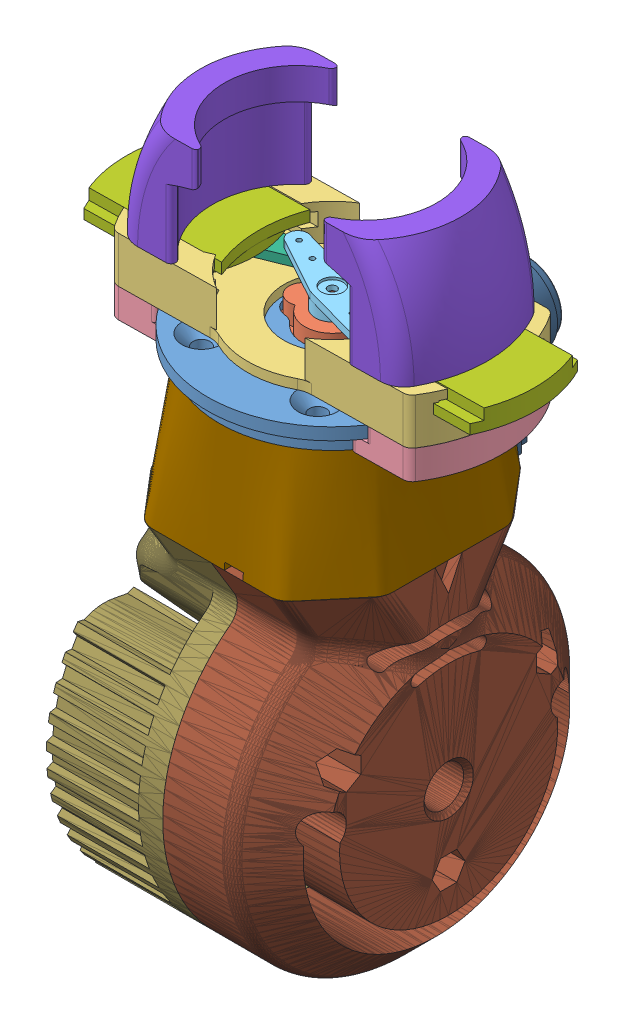
SolidWorks assembly Схват2, configuration По умолчанию. Lengths in mm.
Overall size (84.15 139 75.5).
16 component instances, 12 part files, 77 mates.
Components (placement in the parent):
- Рельс_v3-1: Рельс_v3 [По умолчанию] at (-57.4997 -6.93 31.9738) size (51.5 6 51.5)
- servo_micro-1: servo_micro [По умолчанию] at (-45.8497 -25.18 12.7238) x (1 0 0) z (0 -1 0) size (33 12.5 29.75)
- Рельс_3-1: Рельс_3 [По умолчанию] at (1.2832 -0.68 3.5473) x (-0.999898 0 0.01427) z (-0.01427 0 -0.999898) size (69.76 9.5 35)
- Накладка-1: Накладка [По умолчанию] at (-28.4997 -6.68 18.9738) x (-0.999898 0 0.01427) z (-0.01427 0 -0.999898) size (16.69 6 30)
- Накладка-2: Накладка [По умолчанию] at (-28.4997 -6.68 18.9738) x (0.999898 0 -0.01427) z (0.01427 0 0.999898) size (16.69 6 30)
- servo_lever-1: servo_lever [По умолчанию] at (-28.4997 6.07 18.9738) x (-0.377303 0 0.92609) z (0.92609 0 0.377303) size (7 4 30)
- Балка_2_EDIT-1: Балка_2_EDIT [По умолчанию] at (-0.0451 4.57 19.0678) x (-0.964486 0 0.264133) z (0.264133 0 0.964486) size (23 1.8 6.5)
- Каретка_новая-1: Каретка_новая [По умолчанию] at (-15.8829 4.82 30.545) x (0.999898 0 -0.01427) z (0.01427 0 0.999898) size (28.74 4.25 22.5)
- Клешня-4: Клешня [По умолчанию] at (-21.5429 24.07 19.3746) x (0.36946 0 -0.929246) z (-0.929246 0 -0.36946) size (35.38 23 27.01)
- Балка_2_EDIT-3: Балка_2_EDIT [По умолчанию] at (-56.6495 4.57 19.8756) x (0.947068 0 -0.321033) z (-0.321033 0 -0.947068) size (23 1.8 6.5)
- Каретка_новая-2: Каретка_новая [По умолчанию] at (-40.8117 4.57 8.3985) x (-0.999898 0 0.01427) z (-0.01427 0 -0.999898) size (28.74 4.25 22.5)
- Клешня-5: Клешня [По умолчанию] at (-35.1517 23.82 19.5688) x (-0.36946 0 0.929246) z (0.929246 0 0.36946) size (35.38 23 27.01)
- Цилиндр_v2-1: Цилиндр_v2 [По умолчанию] at (-28.4997 -6.93 18.9738) x (0 0 1) z (1 0 0) size (50 24 48)
- камера.камера_pi-2: камера.камера_pi [По умолчанию] at (-28.4997 -18.93 -7.5262) x (1 0 0) z (0 -1 0) size (25 16 24)
- 4M2B-1: 4M2B [По умолчанию] at (-28.4997 -30.93 53.9739) x (0 0 -1) z (0 -1 0) size (70 24.36 76)
- 4M2CB-1: 4M2CB [По умолчанию] at (-28.4997 -30.93 -16.0262) x (0 0 1) z (0 -1 0) size (70 24 76)
Mates (geometry in assembly coordinates):
- Концентричный1: concentric anti-aligned: cylinder of Рельс_v3-1 through (-28.3805 -6.93 19.0685) axis (0 1 0) radius 6.25; cylinder of servo_micro-1 through (-28.3805 1.57 19.0685) axis (0 -1 0) radius 5.65
- Совпадение1: coincident anti-aligned: plane of Рельс_v3-1 through (-57.2765 -2.43 32.2979) normal (0 -1 0); plane of servo_micro-1 through (-45.6804 -2.43 25.4558) normal (0 1 0)
- Параллельность1: parallel anti-aligned: plane of Рельс_v3-1 through (-57.328 -2.43 25.7981) normal (-0.007926 0 -0.999969); plane of servo_micro-1 through (-45.6804 -25.18 25.4558) normal (0.007926 0 0.999969)
- Расстояние1: distance = 0.25 mm anti-aligned: plane of Рельс_3-1 through (-37.8772 -0.68 19.1077) normal (0 -1 0); plane of Рельс_v3-1 through (-57.4997 -0.93 31.9738) normal (0 1 0)
- Совпадение5: coincident anti-aligned: plane of Рельс_3-1 through (36.0626 6.25 -13) normal (0 -1 0); plane of ? through (21.0476 6.25 1.2686) normal (0 1 0)
- Совпадение6: coincident anti-aligned: plane of Рельс_3-1 through (-37.7579 -0.68 19.2023) normal (0 -1 0); plane of Накладка-1 through (-28.3805 -0.68 19.0685) normal (0 1 0)
- Концентричный4: concentric anti-aligned: cylinder of Рельс_3-1 through (-57.6857 8.82 25.4873) axis (0 -1 0) radius 1.35; cylinder of Накладка-1 through (-57.6857 -6.68 25.4873) axis (0 1 0) radius 1.35
- Концентричный5: concentric anti-aligned: cylinder of Рельс_3-1 through (-57.857 8.82 13.4886) axis (0 -1 0) radius 1.35; cylinder of Накладка-1 through (-57.857 -6.68 13.4886) axis (0 1 0) radius 1.35
- Совпадение7: coincident anti-aligned: plane of Рельс_3-1 through (-37.7579 -0.68 19.2023) normal (0 -1 0); plane of Накладка-2 through (-28.3805 -0.68 19.0685) normal (0 1 0)
- Концентричный6: concentric anti-aligned: cylinder of Рельс_3-1 through (0.9248 8.82 12.6496) axis (0 -1 0) radius 1.35; cylinder of Накладка-2 through (0.9248 -6.68 12.6496) axis (0 1 0) radius 1.35
- Концентричный7: concentric anti-aligned: cylinder of Рельс_3-1 through (1.096 8.82 24.6484) axis (0 -1 0) radius 1.35; cylinder of Накладка-2 through (1.096 -6.68 24.6484) axis (0 1 0) radius 1.35
- Совпадение8: coincident anti-aligned: plane of ? through (38.5525 16 -12.8279) normal (0 1 0); plane of ? through (44.0836 16 3.4423) normal (0 -1 0)
- Концентричный8: concentric anti-aligned: cylinder of ? through (58.6762 11.5 -17.4662) axis (0 1 0) radius 1.15; cylinder of ? through (58.6762 22 -17.4662) axis (0 -1 0) radius 1
- Концентричный9: concentric anti-aligned: cylinder of ? through (58.496 11.5 -7.4678) axis (0 1 0) radius 1.15; cylinder of ? through (58.496 22 -7.4678) axis (0 -1 0) radius 1
- Расстояние2: distance = 0.25 mm anti-aligned: plane of ? through (44.0836 16 3.4423) normal (0 -1 0); plane of Рельс_3-1 through (37.0613 15.75 -12.8548) normal (0 1 0)
- Концентричный10: concentric anti-aligned: cylinder of ? through (-2.1101 22 -8.148) axis (0 -1 0) radius 1; cylinder of ? through (-2.1101 11.5 -8.148) axis (0 1 0) radius 1.15
- Совпадение12: coincident anti-aligned: plane of ? through (12.2041 16 -29.248) normal (0 -1 0); plane of ? through (17.9503 16 -13.0526) normal (0 1 0)
- Концентричный11: concentric anti-aligned: cylinder of ? through (-2.0625 22 -18.1479) axis (0 -1 0) radius 1; cylinder of ? through (-2.0625 11.5 -18.1479) axis (0 1 0) radius 1.15
- Расстояние4: distance = 0.25 mm anti-aligned: plane of ? through (12.2041 16 -29.248) normal (0 -1 0); plane of Рельс_3-1 through (20.9375 15.75 -13.0384) normal (0 1 0)
- Расстояние5: distance = 0.25 mm anti-aligned: plane of Рельс_3-1; plane of ? through (17.9919 16 -21.8025) normal (0.00476 0 -0.999989)
- Совпадение15: coincident anti-aligned: plane of servo_micro-1 through (-28.3805 4.57 19.0685) normal (0 1 0); plane of servo_lever-1 through (-28.3805 4.57 19.0685) normal (0 -1 0)
- Концентричный12: concentric anti-aligned: cylinder of servo_micro-1 through (-28.3805 4.57 19.0685) axis (0 -1 0) radius 2.5; cylinder of servo_lever-1 through (-28.3805 2.07 19.0685) axis (0 1 0) radius 3.5
- Концентричный17: concentric aligned: cylinder of Рельс_v3-1 through (41 6 -1) axis (0 -1 0) radius 1.6; cylinder of ? through (41 0 -1) axis (0 -1 0) radius 3.75
- Совпадение19: coincident anti-aligned: plane of Рельс_v3-1 through (0 0 0) normal (0 -1 0); plane of ? through (41 0 -1) normal (0 1 0)
- Концентричный18: concentric aligned: cylinder of Рельс_v3-1 through (17 6 -1) axis (0 -1 0) radius 1.6; cylinder of ? through (17 0 -1) axis (0 -1 0) radius 3.75
- Совпадение20: coincident anti-aligned: plane of Рельс_v3-1 through (0 0 0) normal (0 -1 0); plane of ? through (17 0 -1) normal (0 1 0)
- Совпадение21: coincident anti-aligned: plane of Рельс_v3-1 through (0 0 0) normal (0 -1 0); plane of ? through (20.5 0 -27.7224) normal (0 1 0)
- Концентричный19: concentric aligned: cylinder of Рельс_v3-1 through (20.5 6 -27.7224) axis (0 -1 0) radius 1.6; cylinder of ? through (20.5 0 -27.7224) axis (0 -1 0) radius 3.75
- Совпадение22: coincident anti-aligned: plane of Рельс_v3-1 through (0 0 0) normal (0 -1 0); plane of ? through (41 0 -25) normal (0 1 0)
- Концентричный20: concentric aligned: cylinder of Рельс_v3-1 through (41 6 -25) axis (0 -1 0) radius 1.6; cylinder of ? through (41 0 -25) axis (0 -1 0) radius 3.75
- Совпадение23: coincident anti-aligned: plane of ? through (17 -22 -1) normal (0 -1 0); plane of ? through (-5.6482 -22 -12.2929) normal (0 1 0)
- Концентричный21: concentric: cylinder of ? through (17 0 -1) axis (0 -1 0) radius 1.65; cylinder of ? through (17 -24.5 -1) axis (0 1 0) radius 1.6
- Концентричный22: concentric: cylinder of ? through (17 0 -25) axis (0 -1 0) radius 1.65; cylinder of ? through (17 -24.5 -25) axis (0 1 0) radius 1.6
- Концентричный23: concentric aligned: cylinder of Рельс_v3-1 through (20.5 6 -27.7224) axis (0 -1 0) radius 1.6; cylinder of ? through (20.5 0 -27.7224) axis (0 -1 0) radius 1.65
- Совпадение24: coincident anti-aligned: plane of Рельс_v3-1 through (0 0 0) normal (0 -1 0); plane of ? through (20.5 0 -27.7224) normal (0 1 0)
- Концентричный24: concentric aligned: cylinder of Рельс_v3-1 through (46 6 -13) axis (0 -1 0) radius 1.6; cylinder of ? through (46 0 -13) axis (0 -1 0) radius 3.75
- Концентричный25: concentric aligned: cylinder of Рельс_v3-1 through (20.5 6 1.7224) axis (0 -1 0) radius 1.6; cylinder of ? through (20.5 0 1.7224) axis (0 -1 0) radius 3.75
- Совпадение25: coincident anti-aligned: plane of Рельс_v3-1 through (0 0 0) normal (0 -1 0); plane of ? through (20.5 0 1.7224) normal (0 1 0)
- Совпадение26: coincident anti-aligned: plane of Рельс_v3-1 through (0 0 0) normal (0 -1 0); plane of ? through (46 0 -13) normal (0 1 0)
- Концентричный26: concentric anti-aligned: cylinder of ? through (46 -24.5 -13) axis (0 1 0) radius 1.6; cylinder of ? through (46 0 -13) axis (0 -1 0) radius 1.65
- Концентричный27: concentric anti-aligned: cylinder of ? through (20.5 -24.5 1.7224) axis (0 1 0) radius 1.6; cylinder of ? through (20.5 0 1.7224) axis (0 -1 0) radius 1.65
- Совпадение27: coincident anti-aligned: plane of ? through (-4.6506 -22 -21.2846) normal (0 1 0); plane of ? through (46 -22 -13) normal (0 -1 0)
- Концентричный28: concentric aligned: cylinder of Рельс_v3-1 through (-28.3805 -0.93 19.0685) axis (0 -1 0) radius 25.75; cylinder of Рельс_3-1 through (-28.3805 8.82 19.0685) axis (0 -1 0) radius 10
- Расстояние6: distance = 0.25 mm anti-aligned: plane of ? through (38.3949 16 -4.0793) normal (-0.018013 0 0.999838); plane of Рельс_3-1
- Концентричный29: concentric aligned: cylinder of ? through (29 291.4661 -13) axis (0 1 0) radius 14.75; cylinder of ? through (29 175.9661 -13) axis (0 1 0) radius 17.25
- Совпадение29: coincident anti-aligned: plane of ? through (43.75 175.9661 -13) normal (0 -1 0); plane of ? through (13.4112 175.9661 -10.7521) normal (0 1 0)
- Концентричный30: concentric anti-aligned: cylinder of Рельс_v3-1 through (29 3.5 -13) axis (0 -1 0) radius 23; cylinder of ? through (29 175.9661 -13) axis (0 1 0) radius 17.25
- Концентричный31: concentric aligned: cylinder of servo_lever-1 through (-16.8205 4.57 23.8242) axis (0 1 0) radius 0.5; cylinder of Балка_2_EDIT-1 through (-16.8205 2.77 23.8242) axis (0 1 0) radius 0.9
- Совпадение30: coincident anti-aligned: plane of servo_lever-1 through (-28.3805 4.57 19.0685) normal (0 -1 0); plane of Балка_2_EDIT-1 through (0.0473 4.57 19.1628) normal (0 1 0)
- Концентричный32: concentric anti-aligned: cylinder of ? through (58.9791 16 -12.4599) axis (0 -1 0) radius 1.15; cylinder of Балка_2_EDIT-1 through (58.9791 9.7 -12.4599) axis (0 1 0) radius 1.15
- Расстояние7: distance = 0.25 mm anti-aligned: plane of Рельс_3-1 through (-28.6567 7.07 7.975) normal (0.01427 0 0.999898); plane of Каретка_новая-1 through (-16.204 6.82 8.0473) normal (-0.01427 0 -0.999898)
- Концентричный33: concentric anti-aligned: cylinder of Балка_2_EDIT-1 through (0.0473 2.77 19.1628) axis (0 1 0) radius 1.15; cylinder of Каретка_новая-1 through (0.0473 6.82 19.1628) axis (0 -1 0) radius 1.05
- Расстояние8: distance = 0.25 mm anti-aligned: plane of Каретка_новая-1 through (-15.8829 6.82 30.545) normal (0 1 0); plane of Рельс_3-1 through (-19.1223 7.07 18.84) normal (0 -1 0)
- Совпадение33: coincident anti-aligned: plane of Каретка_новая-1 through (-38.833 9.07 19.7177) normal (0 1 0); plane of Клешня-4 through (-14.5236 9.07 35.5403) normal (0 -1 0)
- Концентричный34: concentric aligned: cylinder of Каретка_новая-1 through (0.0473 6.82 19.1628) axis (0 -1 0) radius 1.05; cylinder of Клешня-4 through (0.0473 13.07 19.1628) axis (0 -1 0) radius 1.15
- Концентричный35: concentric anti-aligned: cylinder of Каретка_новая-1 through (-0.4708 4.82 24.1707) axis (0 1 0) radius 1.15; cylinder of Клешня-4 through (-0.4708 15.07 24.1707) axis (0 -1 0) radius 1
- Концентричный36: concentric aligned: cylinder of servo_lever-1 through (-39.9404 4.57 14.3127) axis (0 1 0) radius 0.5; cylinder of Балка_2_EDIT-3 through (-39.9404 2.77 14.3127) axis (0 1 0) radius 0.9
- Совпадение34: coincident anti-aligned: plane of servo_lever-1 through (-28.3805 4.57 19.0685) normal (0 -1 0); plane of Балка_2_EDIT-3 through (-56.5008 4.57 19.9699) normal (0 1 0)
- Расстояние9: distance = 0.25 mm anti-aligned: plane of Рельс_3-1 through (-37.8772 4.32 19.1077) normal (0 1 0); plane of Каретка_новая-2 through (-40.8117 4.57 8.3985) normal (0 -1 0)
- Расстояние10: distance = 0.25 mm anti-aligned: plane of Каретка_новая-2 through (-40.8117 6.57 8.3985) normal (-0.01427 0 -0.999898); plane of Рельс_3-1 through (-28.6567 7.07 7.975) normal (0.01427 0 0.999898)
- Концентричный37: concentric anti-aligned: cylinder of Балка_2_EDIT-3 through (-56.5008 2.77 19.9699) axis (0 1 0) radius 1.15; cylinder of Каретка_новая-2 through (-56.5008 6.57 19.9699) axis (0 -1 0) radius 1.05
- Совпадение37: coincident anti-aligned: plane of Каретка_новая-2 through (-17.6206 8.82 19.415) normal (0 1 0); plane of Клешня-5 through (-41.93 8.82 3.5924) normal (0 -1 0)
- Концентричный38: concentric anti-aligned: cylinder of Каретка_новая-2 through (-55.8401 4.57 24.9609) axis (0 1 0) radius 1.15; cylinder of Клешня-5 through (-55.8401 14.82 24.9609) axis (0 -1 0) radius 1
- Концентричный39: concentric anti-aligned: cylinder of Каретка_новая-2 through (-55.9828 4.57 14.962) axis (0 1 0) radius 1.15; cylinder of Клешня-5 through (-55.9828 14.82 14.962) axis (0 -1 0) radius 1
- Совпадение38: coincident anti-aligned: plane of Рельс_v3-1 through (-57.2765 -6.93 32.2979) normal (0 -1 0); plane of Цилиндр_v2-1 through (-28.4997 -6.93 18.9738) normal (0 1 0)
- Расстояние11: distance = 0.5 mm anti-aligned: plane of Цилиндр_v2-1 through (-28.4997 -6.93 -6.0262) normal (0 0 -1); plane of камера.камера_pi-2 through (-28.4997 -18.93 -6.5262) normal (0 0 1)
- Совпадение42: coincident aligned: plane of Цилиндр_v2-1 through (-15.9997 -30.93 43.9767) normal (1 0 0); plane of камера.камера_pi-2 through (-15.9997 -30.93 -6.5262) normal (1 0 0)
- Совпадение43: coincident aligned: plane of Цилиндр_v2-1 through (-16.3732 -30.93 -2.0262) normal (0 -1 0); plane of камера.камера_pi-2 through (-15.9997 -30.93 -6.5262) normal (0 -1 0)
- Совпадение44: coincident aligned: plane of 4M2B-1 through (-28.4997 -30.93 53.9739) normal (0 1 0); plane of 4M2CB-1 through (-28.4997 -30.93 -16.0262) normal (0 1 0)
- Совпадение45: coincident anti-aligned: plane of 4M2B-1 through (-28.4997 -30.93 53.9739) normal (-1 0 0); plane of 4M2CB-1 through (-28.4997 -30.93 -16.0262) normal (1 0 0)
- Совпадение46: coincident aligned: line of 4M2B-1 through (-16.1566 -30.93 43.9738) axis (-1 0 0); line of 4M2CB-1 through (-28.4997 -30.93 43.9738) axis (-1 0 0)
- Совпадение47: coincident anti-aligned: plane of Цилиндр_v2-1 through (-16.3732 -30.93 -2.0262) normal (0 -1 0); plane of 4M2B-1 through (-28.4997 -30.93 53.9739) normal (0 1 0)
- Совпадение48: coincident aligned: line of Цилиндр_v2-1 through (-16.3732 -30.93 43.9738) axis (-1 0 0); line of 4M2B-1 through (-16.1566 -30.93 43.9738) axis (-1 0 0)
- Совпадение49: coincident aligned: line of Цилиндр_v2-1 through (-4.4997 -30.93 7.422) axis (0 0 1); line of 4M2B-1 through (-4.4997 -30.93 21.7717) axis (0 0 1)
- Совпадение50: coincident anti-aligned: plane of Рельс_v3-1 through (-57.2765 -6.93 32.2979) normal (0 -1 0); plane of Цилиндр_v2-1 through (-28.4997 -6.93 18.9738) normal (0 1 0)
- Концентричный42: concentric anti-aligned: cylinder of Рельс_v3-1 through (-16.4997 -0.93 3.9738) axis (0 -1 0) radius 1.75; cylinder of Цилиндр_v2-1 through (-16.4997 -30.9318 3.9738) axis (0 1 0) radius 1.75
- Концентричный43: concentric anti-aligned: cylinder of Рельс_v3-1 through (-40.4997 -0.93 3.9738) axis (0 -1 0) radius 1.75; cylinder of Цилиндр_v2-1 through (-40.4997 -30.9318 3.9738) axis (0 1 0) radius 1.75
